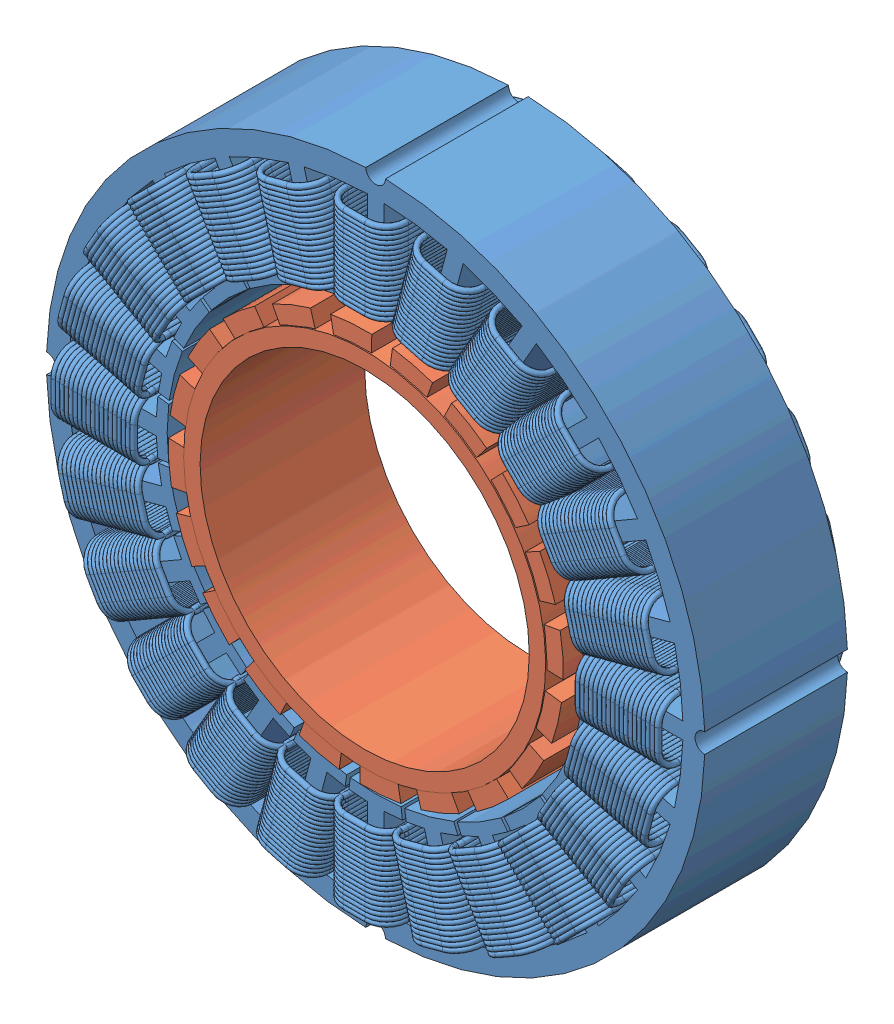
SolidWorks assembly RI60, configuration Default. Lengths in mm.
Overall size (59.97 59.97 17).
2 component instances, 2 part files, 5 mates.
Components (placement in the parent):
- RI60_outer-1: RI60_outer [Default] at origin size (59.97 59.97 17)
- RI60_inrunner-1: RI60_inrunner [Default] at (0 0 -1) x (-0.925537 -0.378656 0) z (0 0 1) size (36 36 15)
Mates (geometry in assembly coordinates):
- Coincident1: coincident aligned: plane of RI60_outer-1 through (0 0 0) normal (0 0 1)
- Coincident2: coincident aligned: plane of RI60_outer-1 through (0 0 0) normal (0 1 0)
- Coincident3: coincident aligned: plane of RI60_outer-1 through (0 0 0) normal (1 0 0)
- Concentric1: concentric aligned: line of RI60_outer-1 through (0 0 13) axis (0 0 -1); cylinder of RI60_inrunner-1 through (0 0 14) axis (0 0 -1) radius 15
- Width1: width anti-aligned: plane of RI60_inrunner-1 through (0 0 -1) normal (0 0 -1); plane of RI60_outer-1 through (0 0 14) normal (0 0 1); plane of RI60_inrunner-1 through (0 0 13) normal (0 0 1); plane of RI60_outer-1 through (0 0 0) normal (0 0 -1)
